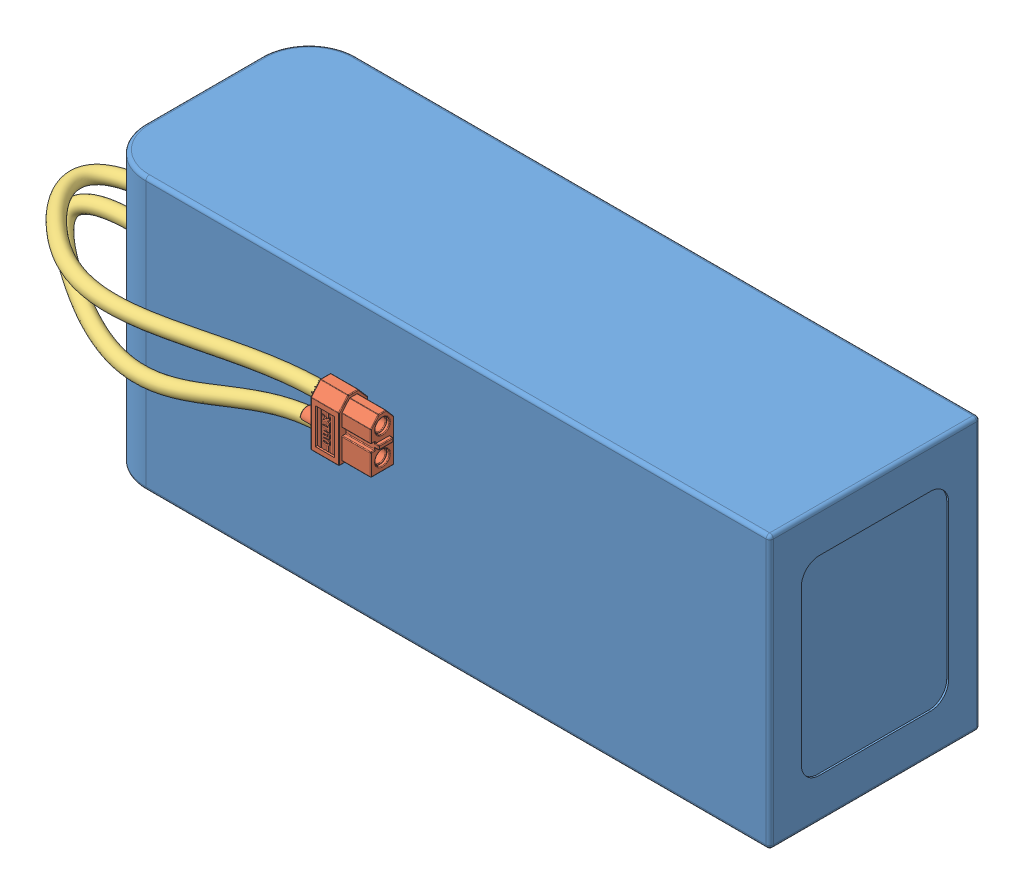
SolidWorks assembly Assembly_Multistar_Battery_3000mah, configuration Default. Lengths in mm.
Overall size (204.94 75 73.22).
3 component instances, 3 part files, 11 mates.
Components (placement in the parent):
- Multistar_3000mAh_4S_Lipo_Battery-1: Multistar_3000mAh_4S_Lipo_Battery [Default] at origin size (185 75 58)
- XT60 Buchse-1: XT60 Buchse [Default] at (-49.555 26.3403 47) x (0 -1 0) z (1 0 0) size (15.68 8.11 21.83)
- Part3^Assembly_Multistar_Battery_3000mah-1: Part3^Assembly_Multistar_Battery_3000mah [Default] at (-115.5 22.9622 26.0496) x (0 -0.017446 0.999848) z (-1 0 0) size (36.99 24.06 86.25) (virtual)
Mates (geometry in assembly coordinates):
- Coincident1: coincident aligned: plane of Multistar_3000mAh_4S_Lipo_Battery-1 through (0 0 0) normal (0 0 1); plane of assembly through (0 0 0) normal (0 0 1)
- Coincident2: coincident aligned: plane of Multistar_3000mAh_4S_Lipo_Battery-1 through (0 0 0) normal (0 1 0); plane of assembly through (0 0 0) normal (0 1 0)
- Coincident3: coincident aligned: plane of Multistar_3000mAh_4S_Lipo_Battery-1 through (0 0 0) normal (1 0 0); plane of assembly through (0 0 0) normal (1 0 0)
- Coincident4: coincident: plane of XT60 Buchse-1 through (-41.755 19.3403 50.2) normal (0 -1 0); plane of ? through (-29.1151 11.0564 -23.9989) normal (-0.008726 -0.999924 -0.008725)
- Coincident5: coincident: plane of XT60 Buchse-1 through (-41.755 19.3403 43.8) normal (0 0 -1); plane of ? through (-29.2154 -0.4443 -24.0992) normal (-0.000228 -0.008724 0.999962)
- Distance1: distance = 15 mm: plane of ? through (-29.1713 4.6739 -20.8545) normal (0.999962 -0.008727 0.000152); plane of XT60 Buchse-1 through (-33.755 25.7883 47) normal (1 0 0)
- Coincident7: coincident anti-aligned: plane of Multistar_3000mAh_4S_Lipo_Battery-1 through (-115.5 -4.625 0.25) normal (-1 0 0); plane of Part3^Assembly_Multistar_Battery_3000mah-1 through (-115.5 31.0483 21.19) normal (1 0 0)
- Coincident8: coincident anti-aligned: plane of Multistar_3000mAh_4S_Lipo_Battery-1 through (0 0 43) normal (0 0 1); plane of XT60 Buchse-1 through (-49.555 18.5403 43) normal (0 0 -1)
- Parallel1: parallel aligned: plane of Multistar_3000mAh_4S_Lipo_Battery-1 through (69 -22 43) normal (0 -1 0); plane of XT60 Buchse-1 through (-49.555 18.5403 51) normal (0 -1 0)
- Concentric1: concentric aligned: circle of XT60 Buchse-1; circle of Part3^Assembly_Multistar_Battery_3000mah-1
- Coincident10: coincident anti-aligned: circle of XT60 Buchse-1; plane of Part3^Assembly_Multistar_Battery_3000mah-1 through (-50.655 30.18 48.9996) normal (1 0 0)
